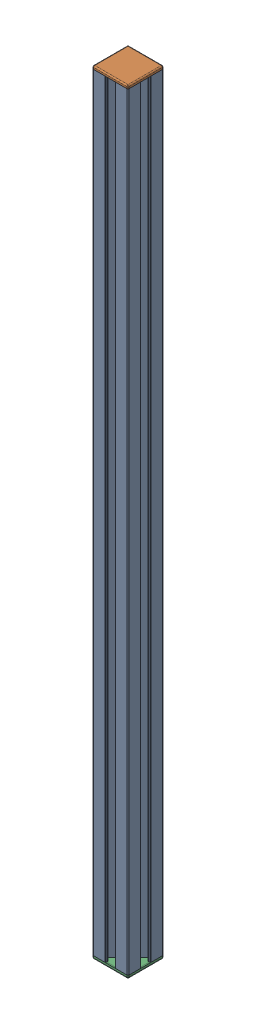
SolidWorks assembly 3cmX3cmX64.9cm Extrusion with Cap, configuration Default. Lengths in mm.
Overall size (30 654 30).
3 component instances, 2 part files, 6 mates.
Components (placement in the parent):
- 3cmX3cmX64.9cm Extrusion2-1: 3cmX3cmX64.9cm Extrusion2 [Default] at (-163.5165 -333.5297 97.8063) size (30 649 30)
- 3cmX3cm Cap2-1: 3cmX3cm Cap2 [Default] at (-163.5165 317.9703 97.8063) x (0 -1 0) z (0 0 1) size (10 30 30)
- 3cmX3cm Cap2-2: 3cmX3cm Cap2 [Default] at (-133.5165 -336.0297 97.8063) x (0 1 0) z (0 0 1) size (10 30 30)
Mates (geometry in assembly coordinates):
- Coincident1: coincident anti-aligned: plane of 3cmX3cmX65.4cm Extrusion2-1 through (-163.5165 315.4703 97.8063) normal (0 1 0); plane of 3cmX3cm Cap2-1 through (-163.5165 315.4703 97.8063) normal (0 -1 0)
- Coincident2: coincident aligned: plane of 3cmX3cmX65.4cm Extrusion2-1 through (-163.5165 315.4703 97.8063) normal (0 0 1); plane of 3cmX3cm Cap2-1 through (-163.5165 315.4703 97.8063) normal (0 0 1)
- Coincident3: coincident aligned: plane of 3cmX3cmX65.4cm Extrusion2-1 through (-133.5165 315.4703 97.8063) normal (1 0 0); plane of 3cmX3cm Cap2-1 through (-133.5165 315.4703 97.8063) normal (1 0 0)
- Coincident4: coincident anti-aligned: plane of 3cmX3cmX65.4cm Extrusion2-1 through (-163.5165 -333.5297 97.8063) normal (0 -1 0); plane of 3cmX3cm Cap2-2 through (-133.5165 -333.5297 97.8063) normal (0 1 0)
- Coincident5: coincident aligned: plane of 3cmX3cmX65.4cm Extrusion2-1 through (-163.5165 315.4703 97.8063) normal (0 0 1); plane of 3cmX3cm Cap2-2 through (-133.5165 -333.5297 97.8063) normal (0 0 1)
- Coincident6: coincident aligned: plane of 3cmX3cmX65.4cm Extrusion2-1 through (-133.5165 315.4703 97.8063) normal (1 0 0); plane of 3cmX3cm Cap2-2 through (-133.5165 -333.5297 97.8063) normal (1 0 0)
